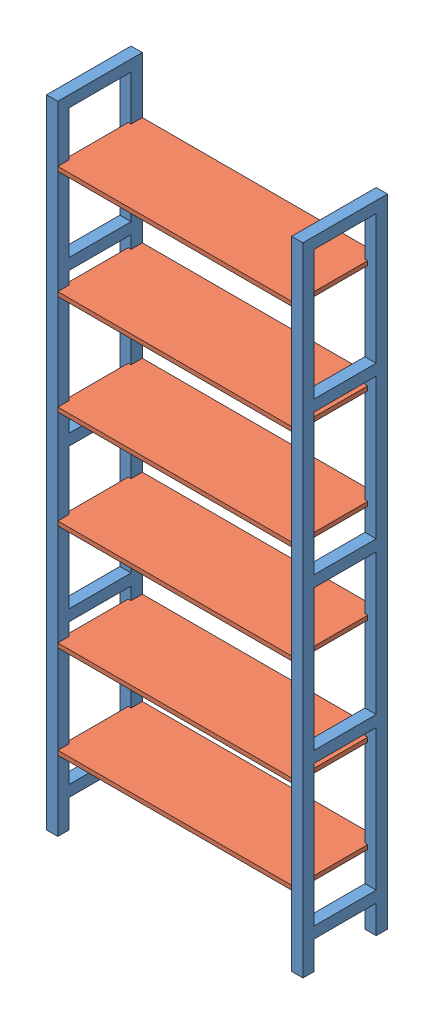
SolidWorks assembly Küchenregal, configuration Standard. Lengths in mm.
Overall size (910 2260 300).
8 component instances, 2 part files, 21 mates.
Components (placement in the parent):
- Seite-30-226-1: Seite-30-226 [Standard] at (-238.8637 -1.8239 2260) size (40 2260 300)
- Seite-30-226-2: Seite-30-226 [Standard] at (631.1363 -1.8239 2260) size (40 2260 300)
- Boden-30-83-1: Boden-30-83 [Standard] at (216.1363 913.1761 2260) size (850 15 300)
- Boden-30-83-2: Boden-30-83 [Standard] at (216.1363 528.1761 2260) size (850 15 300)
- Boden-30-83-3: Boden-30-83 [Standard] at (216.1363 173.1761 2260) size (850 15 300)
- Boden-30-83-4: Boden-30-83 [Standard] at (216.1363 -176.8239 2260) size (850 15 300)
- Boden-30-83-5: Boden-30-83 [Standard] at (216.1363 -551.8239 2260) size (850 15 300)
- Boden-30-83-6: Boden-30-83 [Standard] at (216.1363 -881.8239 2260) size (850 15 300)
Mates (geometry in assembly coordinates):
- Deckungsgleich1: coincident anti-aligned: plane of Seite-30-226-1 through (-198.8637 -1.8239 2260) normal (1 0 0); plane of Boden-30-83-1 through (-198.8637 926.7275 2370) normal (-1 0 0)
- Deckungsgleich2: coincident anti-aligned: plane of Seite-30-226-1 through (-198.8637 -1.8239 2260) normal (1 0 0); plane of Boden-30-83-2 through (-198.8637 543.1761 2370) normal (-1 0 0)
- Deckungsgleich3: coincident anti-aligned: plane of Seite-30-226-1 through (-198.8637 -1.8239 2260) normal (1 0 0); plane of Boden-30-83-3 through (-198.8637 188.1761 2370) normal (-1 0 0)
- Deckungsgleich4: coincident anti-aligned: plane of Seite-30-226-1 through (-198.8637 -1.8239 2260) normal (1 0 0); plane of Boden-30-83-4 through (-198.8637 -161.8239 2370) normal (-1 0 0)
- Deckungsgleich5: coincident anti-aligned: plane of Seite-30-226-1 through (-198.8637 -1.8239 2260) normal (1 0 0); plane of Boden-30-83-6 through (-198.8637 -866.8239 2370) normal (-1 0 0)
- Deckungsgleich6: coincident aligned: plane of Seite-30-226-1 through (-198.8637 1128.1761 2410) normal (0 0 1); plane of Boden-30-83-6 through (-198.8637 -866.8239 2410) normal (0 0 1)
- Deckungsgleich7: coincident aligned: plane of Seite-30-226-1 through (-198.8637 1128.1761 2410) normal (0 0 1); plane of Boden-30-83-5 through (-198.8637 -536.8239 2410) normal (0 0 1)
- Deckungsgleich8: coincident anti-aligned: plane of Seite-30-226-1 through (-198.8637 -1.8239 2260) normal (1 0 0); plane of Boden-30-83-5 through (-198.8637 -536.8239 2370) normal (-1 0 0)
- Deckungsgleich9: coincident aligned: plane of Seite-30-226-1 through (-198.8637 1128.1761 2410) normal (0 0 1); plane of Boden-30-83-4 through (-198.8637 -161.8239 2410) normal (0 0 1)
- Deckungsgleich10: coincident aligned: plane of Seite-30-226-1 through (-198.8637 1128.1761 2410) normal (0 0 1); plane of Boden-30-83-3 through (-198.8637 188.1761 2410) normal (0 0 1)
- Deckungsgleich11: coincident aligned: plane of Seite-30-226-1 through (-198.8637 1128.1761 2410) normal (0 0 1); plane of Boden-30-83-2 through (-198.8637 543.1761 2410) normal (0 0 1)
- Deckungsgleich12: coincident aligned: plane of Seite-30-226-1 through (-198.8637 1128.1761 2410) normal (0 0 1); plane of Boden-30-83-1 through (-198.8637 926.7275 2410) normal (0 0 1)
- Deckungsgleich13: coincident aligned: plane of Seite-30-226-2 through (671.1363 1128.1761 2410) normal (0 0 1); plane of Boden-30-83-1 through (-198.8637 926.7275 2410) normal (0 0 1)
- Deckungsgleich14: coincident anti-aligned: plane of Seite-30-226-2 through (631.1363 -1.8239 2260) normal (-1 0 0); plane of Boden-30-83-1 through (631.1363 926.7275 2410) normal (1 0 0)
- Deckungsgleich15: coincident aligned: plane of Seite-30-226-1 through (-198.8637 1128.1761 2410) normal (0 1 0); plane of Seite-30-226-2 through (671.1363 1128.1761 2410) normal (0 1 0)
- Abstand1: distance = 250 mm aligned: plane of Boden-30-83-6 through (216.1363 -881.8239 2260) normal (0 -1 0); plane of Seite-30-226-2 through (671.1363 -1131.8239 2410) normal (0 -1 0)
- Abstand2: distance = 315 mm anti-aligned: plane of Boden-30-83-5 through (216.1363 -551.8239 2260) normal (0 -1 0); plane of Boden-30-83-6 through (216.1363 -866.8239 2260) normal (0 1 0)
- Abstand3: distance = 360 mm anti-aligned: plane of Boden-30-83-5 through (216.1363 -536.8239 2260) normal (0 1 0); plane of Boden-30-83-4 through (216.1363 -176.8239 2260) normal (0 -1 0)
- Abstand4: distance = 335 mm anti-aligned: plane of Boden-30-83-3 through (216.1363 173.1761 2260) normal (0 -1 0); plane of Boden-30-83-4 through (216.1363 -161.8239 2260) normal (0 1 0)
- Abstand5: distance = 340 mm anti-aligned: plane of Boden-30-83-2 through (216.1363 528.1761 2260) normal (0 -1 0); plane of Boden-30-83-3 through (216.1363 188.1761 2260) normal (0 1 0)
- Abstand6: distance = 370 mm anti-aligned: plane of Boden-30-83-2 through (216.1363 543.1761 2260) normal (0 1 0); plane of Boden-30-83-1 through (216.1363 913.1761 2260) normal (0 -1 0)
